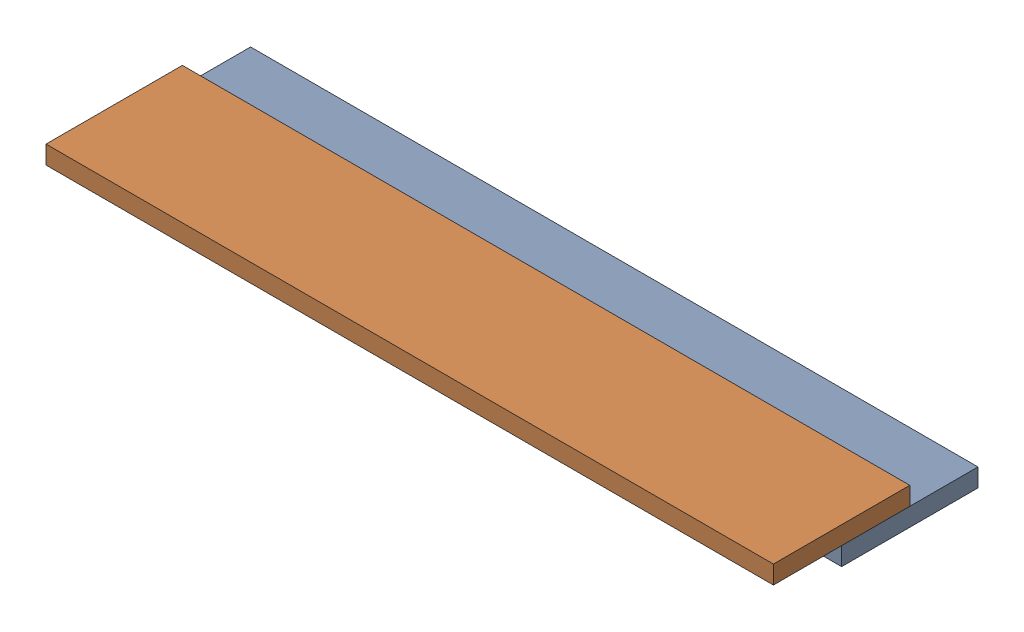
SolidWorks assembly СборкаДЗ, configuration По умолчанию. Lengths in mm.
Overall size (800 40 225).
2 component instances, 1 part files, 3 mates.
Components (placement in the parent):
- ДоскаЗ-1: ДоскаЗ [По умолчанию] at origin size (800 20 150)
- ДоскаЗ-2: ДоскаЗ [По умолчанию] at (0 20 75) size (800 20 150)
Mates (geometry in assembly coordinates):
- Расстояние2: distance = 75 mm aligned: plane of ДоскаЗ-1 through (-400 20 75) normal (0 0 1); plane of ДоскаЗ-2 through (-400 40 150) normal (0 0 1)
- Совпадение4: coincident anti-aligned: plane of ДоскаЗ-1 through (0 20 0) normal (0 1 0); plane of ДоскаЗ-2 through (-20 20 75) normal (0 -1 0)
- Совпадение5: coincident aligned: plane of ДоскаЗ-1 through (400 20 -75) normal (1 0 0); plane of ДоскаЗ-2 through (400 40 0) normal (1 0 0)
